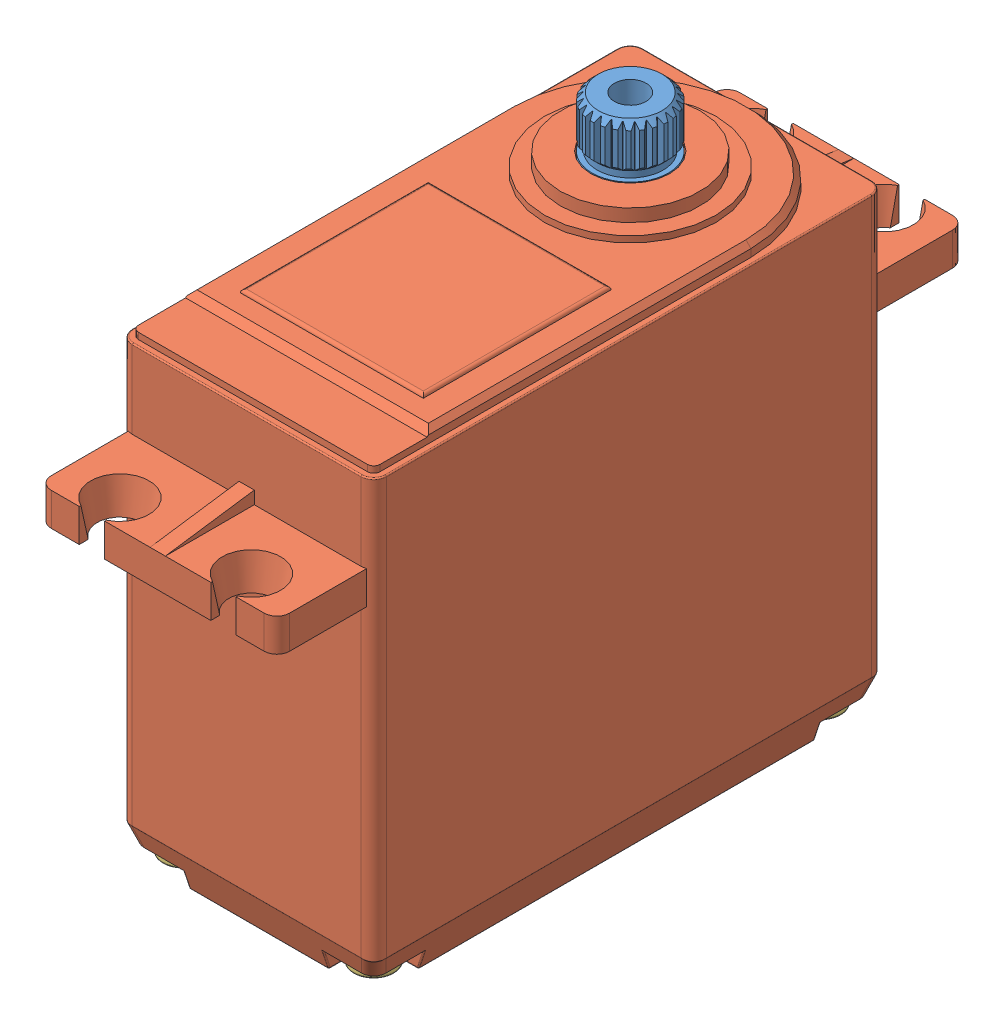
SolidWorks assembly Standard Servo Assembly, configuration Default. Lengths in mm.
Overall size (20.02 42.4 54.21).
6 component instances, 3 part files, 10 mates.
Components (placement in the parent):
- Servo Output Shaft-1: Servo Output Shaft [Default] at (-287.1544 -128.4424 235.7321) size (6 9 6)
- Standard Servo (1501MG)-2: Standard Servo (1501MG) [Default] at (-287.1503 -143.8924 245.8321) x (1 0 -0.00041) z (0.00041 0 1) size (20 38.4 54.2)
- pan head cross recess screw_iso-1: pan head cross recess screw_iso [ISO 7045 - M1.6 x 16 - Z --- 16C] at (-294.6431 -161.6424 263.4352) x (0 1 0) z (0.348576 0 0.937281) size (17.27 3.2 3.2)
- pan head cross recess screw_iso-2: pan head cross recess screw_iso [ISO 7045 - M1.6 x 16 - Z --- 16C] at (-294.6575 -161.6424 228.2352) x (0 1 0) z (0 0 1) size (17.27 3.2 3.2)
- pan head cross recess screw_iso-3: pan head cross recess screw_iso [ISO 7045 - M1.6 x 16 - Z --- 16C] at (-279.6575 -161.6424 228.229) x (0 1 0) z (0 0 1) size (17.27 3.2 3.2)
- pan head cross recess screw_iso-4: pan head cross recess screw_iso [ISO 7045 - M1.6 x 16 - Z --- 16C] at (-279.6431 -161.6424 263.429) x (0 1 0) z (0 0 1) size (17.27 3.2 3.2)
Mates (geometry in assembly coordinates):
- Concentric3: concentric anti-aligned: cylinder of Servo Output Shaft-1 through (-287.1544 -119.4424 235.7321) axis (0 -1 0) radius 3; cylinder of Standard Servo (1501MG)-2 through (-287.1544 -128.4424 235.7321) axis (0 1 0) radius 3.1
- Coincident2: coincident anti-aligned: plane of Servo Output Shaft-1 through (-287.1544 -128.4424 235.7321) normal (0 -1 0); plane of Standard Servo (1501MG)-2 through (-287.1544 -128.4424 235.7321) normal (0 1 0)
- Concentric4: concentric anti-aligned: circle of Standard Servo (1501MG)-2; cylinder of pan head cross recess screw_iso-4 through (-279.6431 -187.0424 263.429) axis (0 -1 0) radius 0.8
- Coincident3: coincident anti-aligned: plane of Standard Servo (1501MG)-2 through (-287.1503 -160.3424 245.8321) normal (0 -1 0); plane of pan head cross recess screw_iso-4 through (-280.4431 -160.3424 263.429) normal (0 1 0)
- Concentric5: concentric aligned: cylinder of Standard Servo (1501MG)-2 through (-294.6431 -130.3424 263.4352) axis (0 -1 0) radius 0.75; cylinder of pan head cross recess screw_iso-1 through (-294.6431 -187.0424 263.4352) axis (0 -1 0) radius 0.8
- Coincident4: coincident anti-aligned: plane of Standard Servo (1501MG)-2 through (-287.1503 -160.3424 245.8321) normal (0 -1 0); plane of pan head cross recess screw_iso-1 through (-295.3929 -160.3424 263.714) normal (0 1 0)
- Concentric6: concentric aligned: cylinder of Standard Servo (1501MG)-2 through (-294.6575 -130.3424 228.2352) axis (0 -1 0) radius 0.75; cylinder of pan head cross recess screw_iso-2 through (-294.6575 -187.0424 228.2352) axis (0 -1 0) radius 0.8
- Coincident5: coincident anti-aligned: plane of Standard Servo (1501MG)-2 through (-287.1503 -160.3424 245.8321) normal (0 -1 0); plane of pan head cross recess screw_iso-2 through (-295.4575 -160.3424 228.2352) normal (0 1 0)
- Concentric7: concentric aligned: cylinder of Standard Servo (1501MG)-2 through (-279.6575 -130.3424 228.229) axis (0 -1 0) radius 0.75; cylinder of pan head cross recess screw_iso-3 through (-279.6575 -187.0424 228.229) axis (0 -1 0) radius 0.8
- Coincident6: coincident anti-aligned: plane of Standard Servo (1501MG)-2 through (-287.1503 -160.3424 245.8321) normal (0 -1 0); plane of pan head cross recess screw_iso-3 through (-280.4575 -160.3424 228.229) normal (0 1 0)
